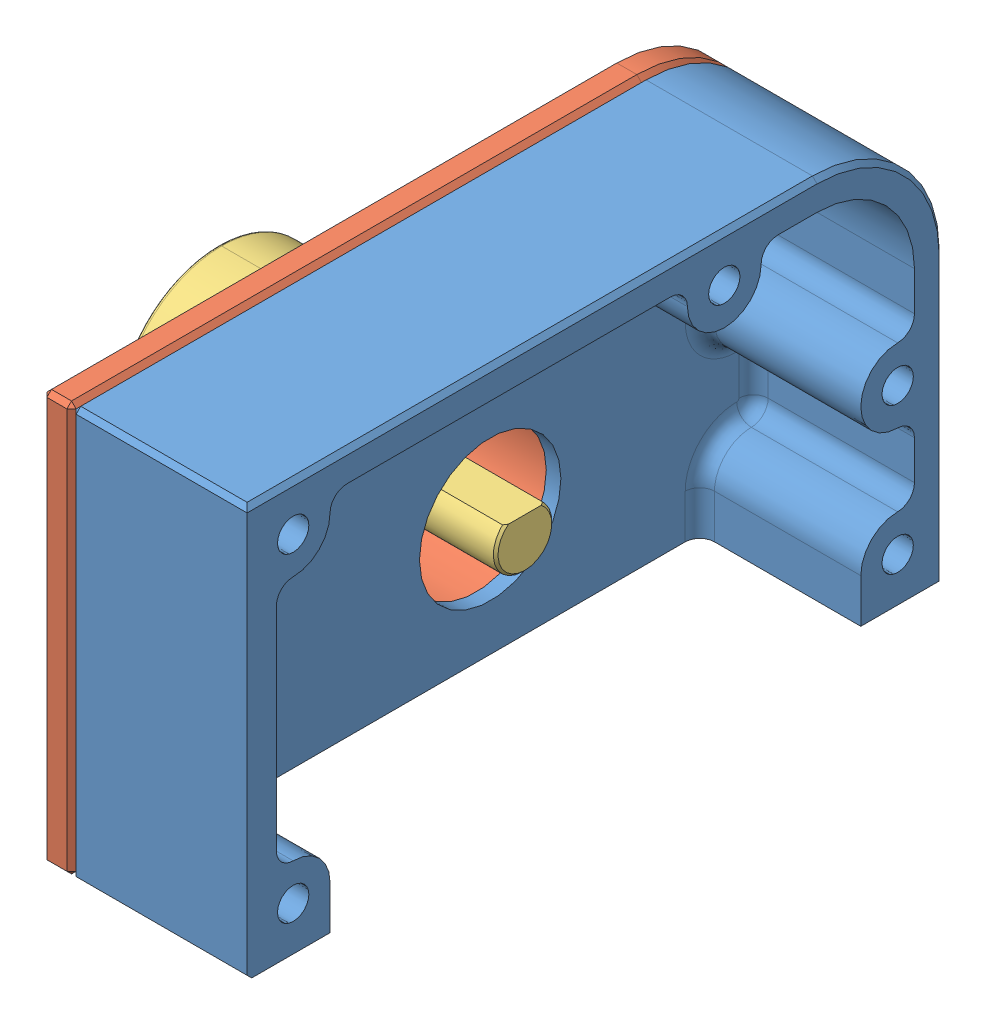
SolidWorks assembly Pitch Sensor Assembly Left(Mirror), configuration Default. Lengths in mm.
Overall size (49.36 44.45 75.59).
3 component instances, 3 part files, 0 mates.
Components (placement in the parent):
- Pitch Sensor Assembly Left(Mirror)-1: Pitch Sensor Assembly Left(Mirror) [Default] at origin size (19.05 44.45 75.59)
- Pitch Sensor Assembly Left(Mirror)_2-1: Pitch Sensor Assembly Left(Mirror)_2 [Default] at origin size (16.83 44.45 75.59)
- 6127V1AxxxL.5FS-1: 6127V1AxxxL.5FS [6127V1A90L.5FS] at (57.3734 63 -43.8404) x (0 -1 0) z (0 0 -1) size (22.23 35.66 22.23)
